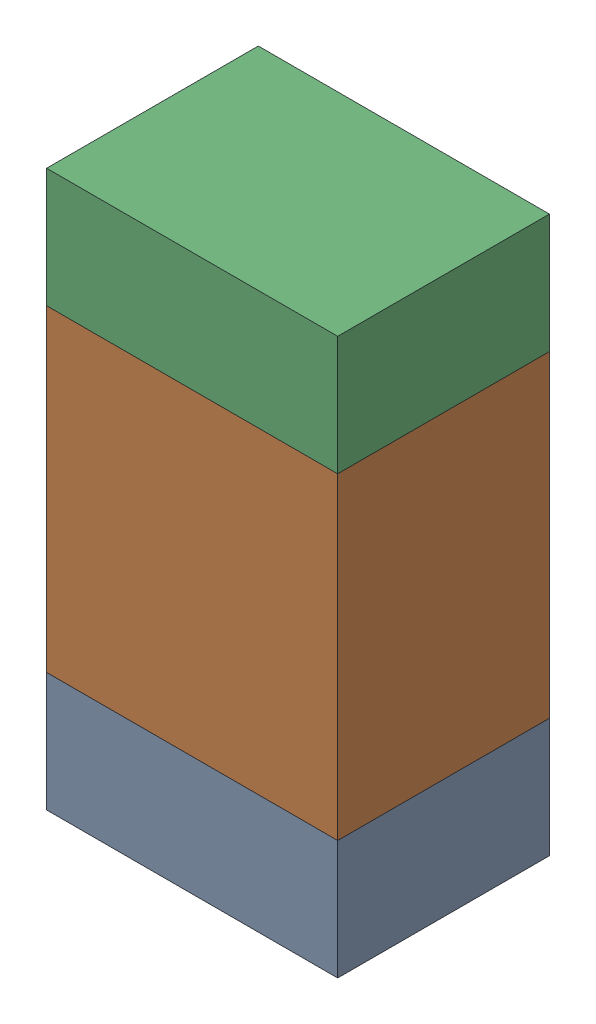
SolidWorks assembly R603_2PCB, configuration Default. Lengths in mm.
Overall size (0.55 1.05 0.4).
6 component instances, 2 part files, 0 mates.
Components (placement in the parent):
- 846483288-1: 846483288 [Default] at (104.0001 102.4876 -2.0638) size (0.55 0.22 0.4)
  - Extruded_12-1: Extruded_12 [Default] at origin size (0.55 0.22 0.4)
- 846483424-1: 846483424 [Default] at (104.0001 102.9001 -2.0638) size (0.55 0.6 0.4)
  - Extruded_13-1: Extruded_13 [Default] at origin size (0.55 0.6 0.4)
- 846483288-2: 846483288 [Default] at (104.0001 103.3126 -2.0638) size (0.55 0.22 0.4)
  - Extruded_12-1: Extruded_12 [Default] at origin size (0.55 0.22 0.4)
